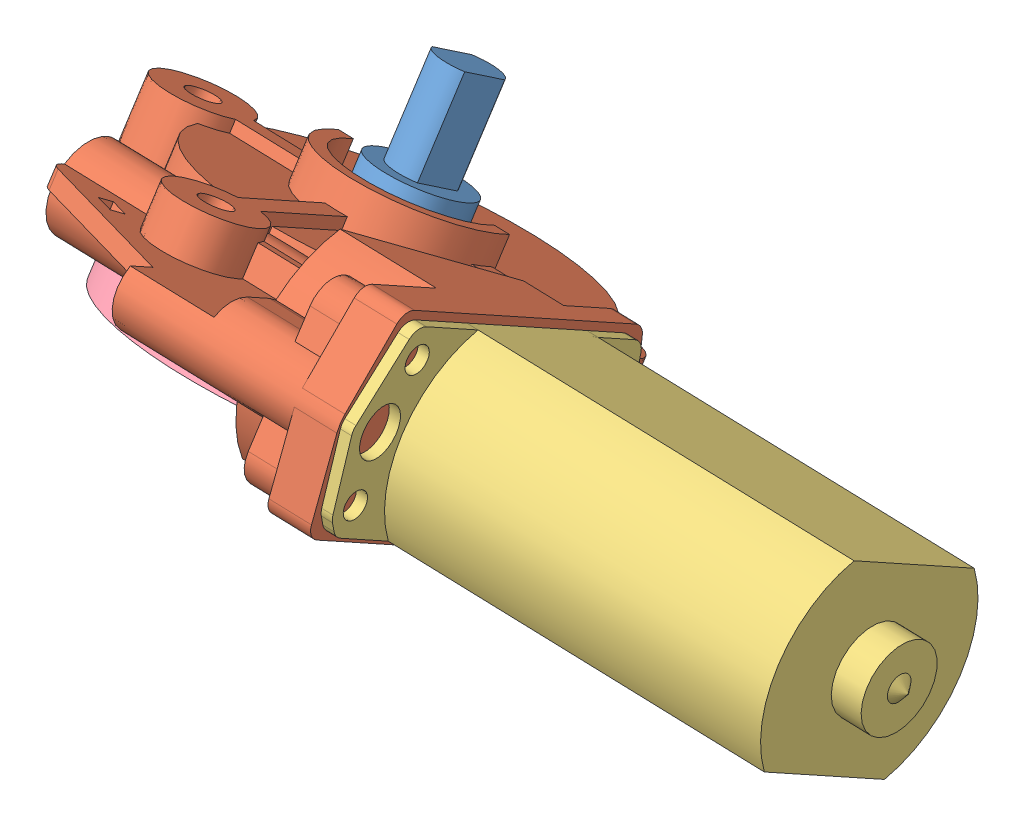
SolidWorks assembly AM-2235 SnowBlower Motor, configuration Default. Lengths in mm.
Overall size (161.23 78.96 97.93).
4 component instances, 4 part files, 7 mates.
Components (placement in the parent):
- AM-2235 output shaft-1: AM-2235 output shaft [Default] at (-65.1618 3.7945 44.1606) x (0.975465 0.078473 0.205693) z (0.03631 0.864173 -0.501883) size (15.85 15.85 21.62)
- AM-2235 gearbox housing-1: AM-2235 gearbox housing [Default] at (-65.9125 -14.0728 54.5374) x (-0.998192 0.055439 0.023242) z (0.03631 0.864173 -0.501883) size (83.55 92.74 31.5)
- AM-2235 motor-1: AM-2235 motor [Default] at (44.1054 -13.0167 83.8) x (0.03631 0.864173 -0.501883) z (0.998192 -0.055439 -0.023242) size (28.96 59.84 72.44)
- AM-2235 gear cap-1: AM-2235 gear cap [Default] at (-66.7241 -33.3888 65.7555) x (0.962035 -0.166165 -0.216512) z (0.03631 0.864173 -0.501883) size (65.41 65.41 6.35)
Mates (geometry in assembly coordinates):
- Concentric1: concentric: AM-2235 output shaft-1, AM-2235 gearbox housing-1
- Coincident1: coincident: AM-2235 gearbox housing-1, AM-2235 gear cap-1
- Width1: width: AM-2235 gearbox housing-1, AM-2235 motor-1
- Coincident2: coincident: AM-2235 gearbox housing-1, AM-2235 motor-1
- Distance2: distance: AM-2235 gearbox housing-1, AM-2235 motor-1
- Distance3: distance: AM-2235 output shaft-1, AM-2235 gearbox housing-1
- Concentric2: concentric: AM-2235 gearbox housing-1, AM-2235 gear cap-1
